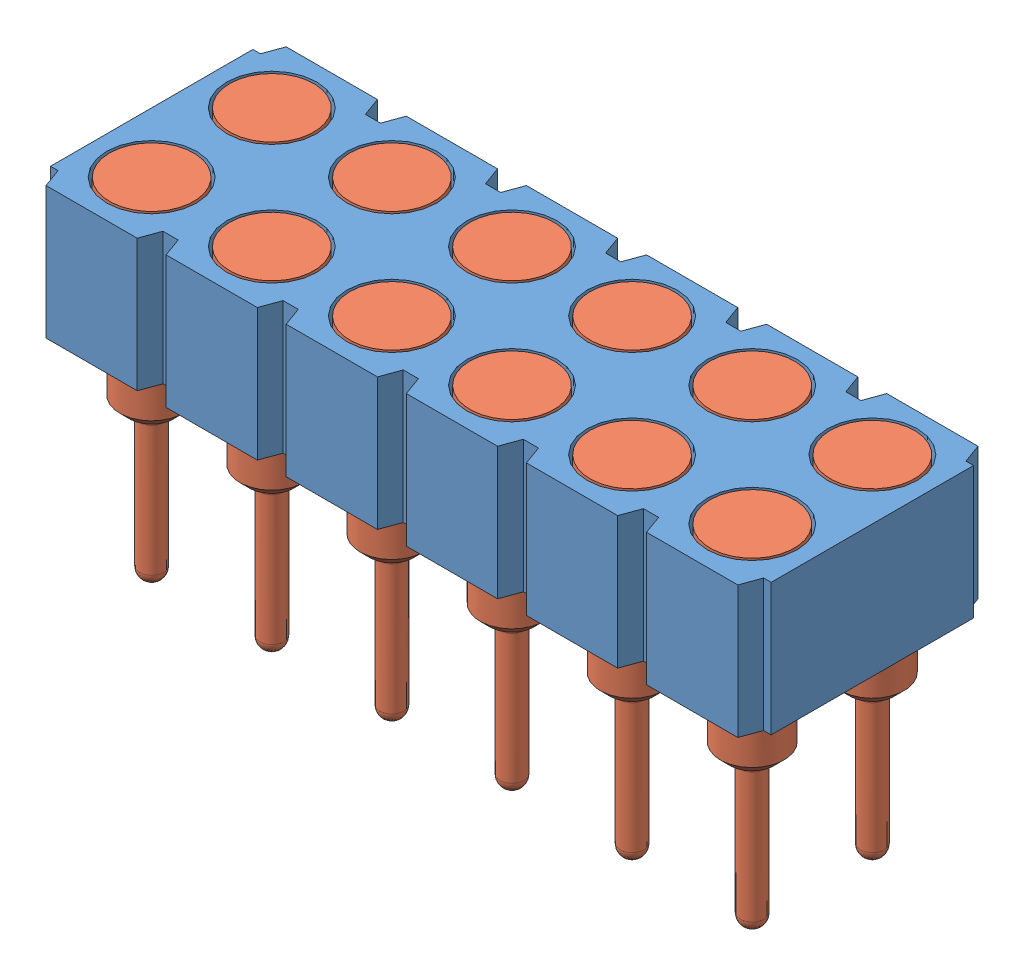
SolidWorks assembly mill-max-419-10-212-00-001000, configuration Default. Lengths in mm.
Overall size (15.24 7.37 5.08).
13 component instances, 2 part files, 0 mates.
Components (placement in the parent):
- mill-max-419-10-212-00-001000_P4XX-21-010-00-000000-1: mill-max-419-10-212-00-001000_P4XX-21-010-00-000000 [Default] at origin size (15.24 2.79 5.08)
- mill-max-419-10-212-00-001000_1942-1: mill-max-419-10-212-00-001000_1942 [Default] at (0.9644 0 -1.27) x (0 -1 0) z (0 0 1) size (7.37 1.78 1.78)
- mill-max-419-10-212-00-001000_1942-2: mill-max-419-10-212-00-001000_1942 [Default] at (0.9644 0 -3.81) x (0 -1 0) z (0 0 1) size (7.37 1.78 1.78)
- mill-max-419-10-212-00-001000_1942-3: mill-max-419-10-212-00-001000_1942 [Default] at (3.5044 0 -3.81) x (0 -1 0) z (0 0 1) size (7.37 1.78 1.78)
- mill-max-419-10-212-00-001000_1942-4: mill-max-419-10-212-00-001000_1942 [Default] at (3.5044 0 -1.27) x (0 -1 0) z (0 0 1) size (7.37 1.78 1.78)
- mill-max-419-10-212-00-001000_1942-5: mill-max-419-10-212-00-001000_1942 [Default] at (6.0444 0 -3.81) x (0 -1 0) z (0 0 1) size (7.37 1.78 1.78)
- mill-max-419-10-212-00-001000_1942-6: mill-max-419-10-212-00-001000_1942 [Default] at (8.5844 0 -3.81) x (0 -1 0) z (0 0 1) size (7.37 1.78 1.78)
- mill-max-419-10-212-00-001000_1942-7: mill-max-419-10-212-00-001000_1942 [Default] at (11.1244 0 -3.81) x (0 -1 0) z (0 0 1) size (7.37 1.78 1.78)
- mill-max-419-10-212-00-001000_1942-8: mill-max-419-10-212-00-001000_1942 [Default] at (13.6644 0 -3.81) x (0 -1 0) z (0 0 1) size (7.37 1.78 1.78)
- mill-max-419-10-212-00-001000_1942-9: mill-max-419-10-212-00-001000_1942 [Default] at (6.0444 0 -1.27) x (0 -1 0) z (0 0 1) size (7.37 1.78 1.78)
- mill-max-419-10-212-00-001000_1942-10: mill-max-419-10-212-00-001000_1942 [Default] at (8.5844 0 -1.27) x (0 -1 0) z (0 0 1) size (7.37 1.78 1.78)
- mill-max-419-10-212-00-001000_1942-11: mill-max-419-10-212-00-001000_1942 [Default] at (11.1244 0 -1.27) x (0 -1 0) z (0 0 1) size (7.37 1.78 1.78)
- mill-max-419-10-212-00-001000_1942-12: mill-max-419-10-212-00-001000_1942 [Default] at (13.6644 0 -1.27) x (0 -1 0) z (0 0 1) size (7.37 1.78 1.78)
